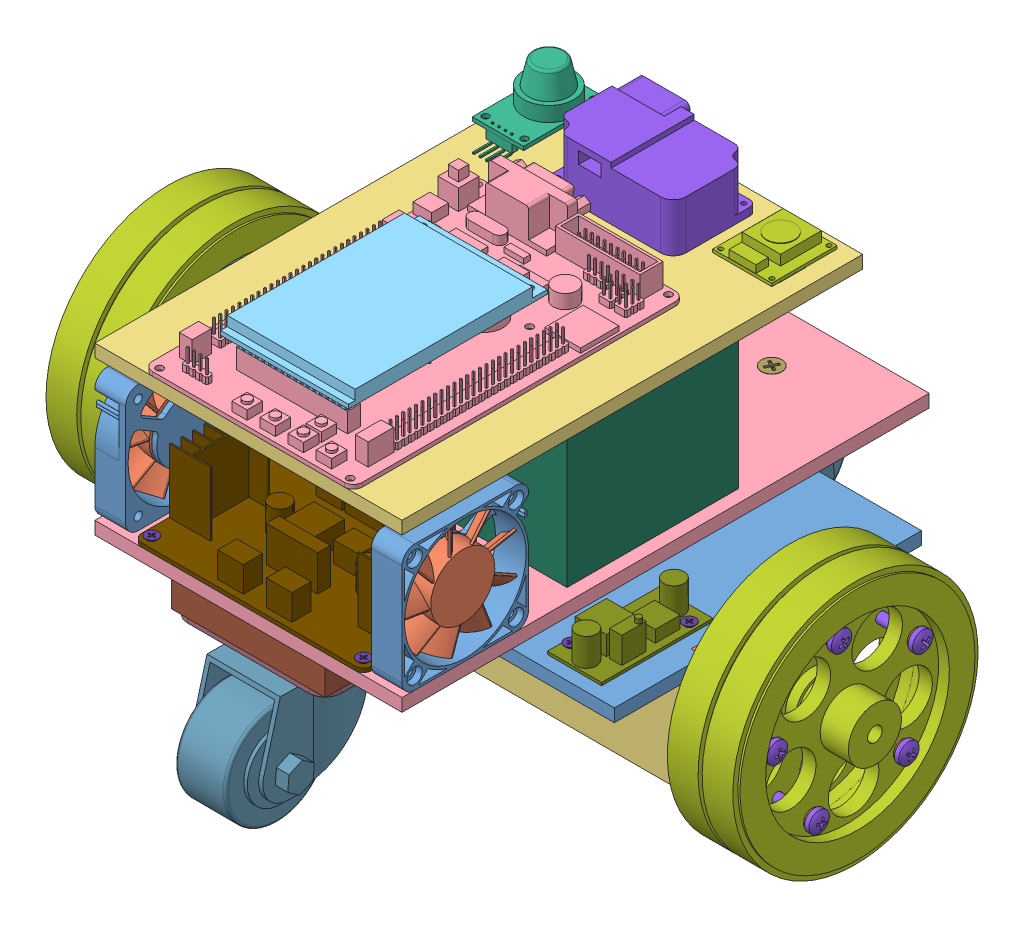
SolidWorks assembly MACM000000_MACMAssy, configuration 默认. Lengths in mm.
Overall size (283.6 176.7 243.22).
103 component instances, 26 part files, 3 mates.
Components (placement in the parent):
- MACM010000_BaseAssy-1: MACM010000_BaseAssy [默认] at (-30.595 3.8524 77.6) size (283.6 149.04 243.22)
  - MACM010100_Base-1: MACM010100_Base [默认] at (-8.5802 22.7565 6) size (200 55 206)
    - MACM010103_BasePlateC-1: MACM010103_BasePlateC [默认] at (5.4574 14.5542 200) size (200 5 120)
    - MACM010101_BasePlateA-1: MACM010101_BasePlateA [默认] at (-89.5426 -5.4458 200) x (0 0 1) z (0 -1 0) size (50 5 50)
    - MACM010101_BasePlateA-3: MACM010101_BasePlateA [默认] at (105.4574 -5.4458 200) x (0 0 1) z (0 -1 0) size (50 5 50)
    - MACM010102_BasePlateB-1: MACM010102_BasePlateB [默认] at (5.4574 -7.9458 225) x (-1 0 0) z (0 -1 0) size (200 5 45)
    - MACM010102_BasePlateB-3: MACM010102_BasePlateB [默认] at (5.4574 -7.9458 180) x (-1 0 0) z (0 -1 0) size (200 5 45)
    - MACM010104_BasePlateD-1: MACM010104_BasePlateD [默认] at (5.4574 19.5542 200) x (0 0 1) z (-1 0 0) size (206 5 120)
  - MACM010001_Motor_75w-1: MACM010001_Motor_75w [默认] at (-98.1229 17.3107 206) size (106.7 37 37)
  - MACM010001_Motor_75w-3: MACM010001_Motor_75w [默认] at (91.8771 17.3107 206) x (-1 0 0) z (0 0 -1) size (106.7 37 37)
  - GB_CROSS_SCREWS_TYPE1 M3X12-12  H type-N-1: GB_CROSS_SCREWS_TYPE1 M3X12-12  H type-N [GB_CROSS_SCREWS_TYPE1 M3X12-12  H type-N] at (-105.5229 30.7341 198.25) size (14.39 5.6 5.6)
  - GB_CROSS_SCREWS_TYPE1 M3X12-12  H type-N-2: GB_CROSS_SCREWS_TYPE1 M3X12-12  H type-N [GB_CROSS_SCREWS_TYPE1 M3X12-12  H type-N] at (-105.5229 17.3107 190.5) x (1 0 0) z (0 0.866025 0.5) size (14.39 5.6 5.6)
  - GB_CROSS_SCREWS_TYPE1 M3X12-12  H type-N-3: GB_CROSS_SCREWS_TYPE1 M3X12-12  H type-N [GB_CROSS_SCREWS_TYPE1 M3X12-12  H type-N] at (-105.5229 3.8873 198.25) x (1 0 0) z (0 0.866025 -0.5) size (14.39 5.6 5.6)
  - GB_CROSS_SCREWS_TYPE1 M3X12-12  H type-N-4: GB_CROSS_SCREWS_TYPE1 M3X12-12  H type-N [GB_CROSS_SCREWS_TYPE1 M3X12-12  H type-N] at (-105.5229 3.8873 213.75) x (1 0 0) z (0 0 -1) size (14.39 5.6 5.6)
  - GB_CROSS_SCREWS_TYPE1 M3X12-12  H type-N-5: GB_CROSS_SCREWS_TYPE1 M3X12-12  H type-N [GB_CROSS_SCREWS_TYPE1 M3X12-12  H type-N] at (-105.5229 17.3107 221.5) x (1 0 0) z (0 -0.866025 -0.5) size (14.39 5.6 5.6)
  - GB_CROSS_SCREWS_TYPE1 M3X12-12  H type-N-6: GB_CROSS_SCREWS_TYPE1 M3X12-12  H type-N [GB_CROSS_SCREWS_TYPE1 M3X12-12  H type-N] at (-105.5229 30.7341 213.75) x (1 0 0) z (0 -0.866025 0.5) size (14.39 5.6 5.6)
  - GB_CROSS_SCREWS_TYPE1 M3X12-12  H type-N-8: GB_CROSS_SCREWS_TYPE1 M3X12-12  H type-N [GB_CROSS_SCREWS_TYPE1 M3X12-12  H type-N] at (99.2771 3.8873 213.75) x (-1 0 0) z (0 -0.924225 -0.381849) size (14.39 5.6 5.6)
  - GB_CROSS_SCREWS_TYPE1 M3X12-12  H type-N-9: GB_CROSS_SCREWS_TYPE1 M3X12-12  H type-N [GB_CROSS_SCREWS_TYPE1 M3X12-12  H type-N] at (99.2771 3.8873 198.25) x (-1 0 0) z (0 -0.131421 -0.991327) size (14.39 5.6 5.6)
  - GB_CROSS_SCREWS_TYPE1 M3X12-12  H type-N-10: GB_CROSS_SCREWS_TYPE1 M3X12-12  H type-N [GB_CROSS_SCREWS_TYPE1 M3X12-12  H type-N] at (99.2771 17.3107 190.5) x (-1 0 0) z (0 0.792804 -0.609477) size (14.39 5.6 5.6)
  - GB_CROSS_SCREWS_TYPE1 M3X12-12  H type-N-11: GB_CROSS_SCREWS_TYPE1 M3X12-12  H type-N [GB_CROSS_SCREWS_TYPE1 M3X12-12  H type-N] at (99.2771 30.7341 198.25) x (-1 0 0) z (0 0.924225 0.381849) size (14.39 5.6 5.6)
  - GB_CROSS_SCREWS_TYPE1 M3X12-12  H type-N-12: GB_CROSS_SCREWS_TYPE1 M3X12-12  H type-N [GB_CROSS_SCREWS_TYPE1 M3X12-12  H type-N] at (99.2771 30.7341 213.75) x (-1 0 0) z (0 0.131421 0.991327) size (14.39 5.6 5.6)
  - GB_CROSS_SCREWS_TYPE1 M3X12-12  H type-N-13: GB_CROSS_SCREWS_TYPE1 M3X12-12  H type-N [GB_CROSS_SCREWS_TYPE1 M3X12-12  H type-N] at (99.2771 17.3107 221.5) x (-1 0 0) z (0 -0.792804 0.609477) size (14.39 5.6 5.6)
  - MACM010300_DrivingWheel-1: MACM010300_DrivingWheel [默认] at (94.5266 112.8584 231.864) x (-1 0 0) z (0 -0.924225 -0.381849) size (40.8 108.78 108.78)
    - MACM010301_DrivingWheel-1: MACM010301_DrivingWheel [默认] at (-30.5506 -9.9077 91.7141) size (20.4 95.8 95.8)
    - MACM010301_DrivingWheel-2: MACM010301_DrivingWheel [默认] at (-16.9506 -9.9077 91.7141) x (-1 0 0) z (0 -0.989252 -0.146219) size (20.4 95.8 95.8)
    - GB_CROSS_SCREWS_TYPE1 M4X25-25  H type-N-1: GB_CROSS_SCREWS_TYPE1 M4X25-25  H type-N [GB_CROSS_SCREWS_TYPE1 M4X25-25  H type-N] at (-37.3506 -2.9981 62.2638) size (28.07 8 8)
    - GB_FASTENER_WASHER_SW 4-1: GB_FASTENER_WASHER_SW 4 [GB_FASTENER_WASHER_SW 4] at (-33.1506 -2.9981 62.2638) x (0 0 -1) z (1 0 0) size (6.6 6.6 1.1)
    - GB_FASTENER_NUT_SNAB1 M4-N-1: GB_FASTENER_NUT_SNAB1 M4-N [GB_FASTENER_NUT_SNAB1 M4-N] at (-14.3506 -2.9981 62.2638) x (0 0 1) z (-1 0 0) size (8.08 7 3.2)
    - GB_FASTENER_NUT_SNAB1 M4-N-2: GB_FASTENER_NUT_SNAB1 M4-N [GB_FASTENER_NUT_SNAB1 M4-N] at (-14.3506 -35.7814 76.042) x (0 0.951057 0.309017) z (-1 0 0) size (8.08 7 3.2)
    - GB_FASTENER_NUT_SNAB1 M4-N-3: GB_FASTENER_NUT_SNAB1 M4-N [GB_FASTENER_NUT_SNAB1 M4-N] at (-14.3506 -32.8082 111.4785) x (0 0.587785 -0.809017) z (-1 0 0) size (8.08 7 3.2)
    - GB_FASTENER_NUT_SNAB1 M4-N-4: GB_FASTENER_NUT_SNAB1 M4-N [GB_FASTENER_NUT_SNAB1 M4-N] at (-14.3506 1.8127 119.6012) x (0 -0.587785 -0.809017) z (-1 0 0) size (8.08 7 3.2)
    - GB_FASTENER_NUT_SNAB1 M4-N-5: GB_FASTENER_NUT_SNAB1 M4-N [GB_FASTENER_NUT_SNAB1 M4-N] at (-14.3506 20.2364 89.1849) x (0 -0.951057 0.309017) z (-1 0 0) size (8.08 7 3.2)
    - GB_FASTENER_WASHER_SW 4-2: GB_FASTENER_WASHER_SW 4 [GB_FASTENER_WASHER_SW 4] at (-33.1506 -35.7814 76.042) x (0 -0.951057 -0.309017) z (1 0 0) size (6.6 6.6 1.1)
    - GB_FASTENER_WASHER_SW 4-3: GB_FASTENER_WASHER_SW 4 [GB_FASTENER_WASHER_SW 4] at (-33.1506 -32.8082 111.4785) x (0 -0.587785 0.809017) z (1 0 0) size (6.6 6.6 1.1)
    - GB_FASTENER_WASHER_SW 4-4: GB_FASTENER_WASHER_SW 4 [GB_FASTENER_WASHER_SW 4] at (-33.1506 1.8127 119.6012) x (0 0.587785 0.809017) z (1 0 0) size (6.6 6.6 1.1)
    - GB_FASTENER_WASHER_SW 4-5: GB_FASTENER_WASHER_SW 4 [GB_FASTENER_WASHER_SW 4] at (-33.1506 20.2364 89.1849) x (0 0.951057 -0.309017) z (1 0 0) size (6.6 6.6 1.1)
    - GB_CROSS_SCREWS_TYPE1 M4X25-25  H type-N-2: GB_CROSS_SCREWS_TYPE1 M4X25-25  H type-N [GB_CROSS_SCREWS_TYPE1 M4X25-25  H type-N] at (-37.3506 -35.7814 76.042) x (1 0 0) z (0 0.951057 0.309017) size (28.07 8 8)
    - GB_CROSS_SCREWS_TYPE1 M4X25-25  H type-N-3: GB_CROSS_SCREWS_TYPE1 M4X25-25  H type-N [GB_CROSS_SCREWS_TYPE1 M4X25-25  H type-N] at (-37.3506 -32.8082 111.4785) x (1 0 0) z (0 0.587785 -0.809017) size (28.07 8 8)
    - GB_CROSS_SCREWS_TYPE1 M4X25-25  H type-N-4: GB_CROSS_SCREWS_TYPE1 M4X25-25  H type-N [GB_CROSS_SCREWS_TYPE1 M4X25-25  H type-N] at (-37.3506 1.8127 119.6012) x (1 0 0) z (0 -0.587785 -0.809017) size (28.07 8 8)
    - GB_CROSS_SCREWS_TYPE1 M4X25-25  H type-N-5: GB_CROSS_SCREWS_TYPE1 M4X25-25  H type-N [GB_CROSS_SCREWS_TYPE1 M4X25-25  H type-N] at (-37.3506 20.2364 89.1849) x (1 0 0) z (0 -0.951057 0.309017) size (28.07 8 8)
  - MACM010300_DrivingWheel-3: MACM010300_DrivingWheel [默认] at (-100.7723 34.2184 114.2859) size (40.8 108.78 108.78)
    - MACM010301_DrivingWheel-1: MACM010301_DrivingWheel [默认] at (-30.5506 -9.9077 91.7141) size (20.4 95.8 95.8)
    - MACM010301_DrivingWheel-2: MACM010301_DrivingWheel [默认] at (-16.9506 -9.9077 91.7141) x (-1 0 0) z (0 -0.989252 -0.146219) size (20.4 95.8 95.8)
    - GB_CROSS_SCREWS_TYPE1 M4X25-25  H type-N-1: GB_CROSS_SCREWS_TYPE1 M4X25-25  H type-N [GB_CROSS_SCREWS_TYPE1 M4X25-25  H type-N] at (-37.3506 -2.9981 62.2638) size (28.07 8 8)
    - GB_FASTENER_WASHER_SW 4-1: GB_FASTENER_WASHER_SW 4 [GB_FASTENER_WASHER_SW 4] at (-33.1506 -2.9981 62.2638) x (0 0 -1) z (1 0 0) size (6.6 6.6 1.1)
    - GB_FASTENER_NUT_SNAB1 M4-N-1: GB_FASTENER_NUT_SNAB1 M4-N [GB_FASTENER_NUT_SNAB1 M4-N] at (-14.3506 -2.9981 62.2638) x (0 0 1) z (-1 0 0) size (8.08 7 3.2)
    - GB_FASTENER_NUT_SNAB1 M4-N-2: GB_FASTENER_NUT_SNAB1 M4-N [GB_FASTENER_NUT_SNAB1 M4-N] at (-14.3506 -35.7814 76.042) x (0 0.951057 0.309017) z (-1 0 0) size (8.08 7 3.2)
    - GB_FASTENER_NUT_SNAB1 M4-N-3: GB_FASTENER_NUT_SNAB1 M4-N [GB_FASTENER_NUT_SNAB1 M4-N] at (-14.3506 -32.8082 111.4785) x (0 0.587785 -0.809017) z (-1 0 0) size (8.08 7 3.2)
    - GB_FASTENER_NUT_SNAB1 M4-N-4: GB_FASTENER_NUT_SNAB1 M4-N [GB_FASTENER_NUT_SNAB1 M4-N] at (-14.3506 1.8127 119.6012) x (0 -0.587785 -0.809017) z (-1 0 0) size (8.08 7 3.2)
    - GB_FASTENER_NUT_SNAB1 M4-N-5: GB_FASTENER_NUT_SNAB1 M4-N [GB_FASTENER_NUT_SNAB1 M4-N] at (-14.3506 20.2364 89.1849) x (0 -0.951057 0.309017) z (-1 0 0) size (8.08 7 3.2)
    - GB_FASTENER_WASHER_SW 4-2: GB_FASTENER_WASHER_SW 4 [GB_FASTENER_WASHER_SW 4] at (-33.1506 -35.7814 76.042) x (0 -0.951057 -0.309017) z (1 0 0) size (6.6 6.6 1.1)
    - GB_FASTENER_WASHER_SW 4-3: GB_FASTENER_WASHER_SW 4 [GB_FASTENER_WASHER_SW 4] at (-33.1506 -32.8082 111.4785) x (0 -0.587785 0.809017) z (1 0 0) size (6.6 6.6 1.1)
    - GB_FASTENER_WASHER_SW 4-4: GB_FASTENER_WASHER_SW 4 [GB_FASTENER_WASHER_SW 4] at (-33.1506 1.8127 119.6012) x (0 0.587785 0.809017) z (1 0 0) size (6.6 6.6 1.1)
    - GB_FASTENER_WASHER_SW 4-5: GB_FASTENER_WASHER_SW 4 [GB_FASTENER_WASHER_SW 4] at (-33.1506 20.2364 89.1849) x (0 0.951057 -0.309017) z (1 0 0) size (6.6 6.6 1.1)
    - GB_CROSS_SCREWS_TYPE1 M4X25-25  H type-N-2: GB_CROSS_SCREWS_TYPE1 M4X25-25  H type-N [GB_CROSS_SCREWS_TYPE1 M4X25-25  H type-N] at (-37.3506 -35.7814 76.042) x (1 0 0) z (0 0.951057 0.309017) size (28.07 8 8)
    - GB_CROSS_SCREWS_TYPE1 M4X25-25  H type-N-3: GB_CROSS_SCREWS_TYPE1 M4X25-25  H type-N [GB_CROSS_SCREWS_TYPE1 M4X25-25  H type-N] at (-37.3506 -32.8082 111.4785) x (1 0 0) z (0 0.587785 -0.809017) size (28.07 8 8)
    - GB_CROSS_SCREWS_TYPE1 M4X25-25  H type-N-4: GB_CROSS_SCREWS_TYPE1 M4X25-25  H type-N [GB_CROSS_SCREWS_TYPE1 M4X25-25  H type-N] at (-37.3506 1.8127 119.6012) x (1 0 0) z (0 -0.587785 -0.809017) size (28.07 8 8)
    - GB_CROSS_SCREWS_TYPE1 M4X25-25  H type-N-5: GB_CROSS_SCREWS_TYPE1 M4X25-25  H type-N [GB_CROSS_SCREWS_TYPE1 M4X25-25  H type-N] at (-37.3506 20.2364 89.1849) x (1 0 0) z (0 -0.951057 0.309017) size (28.07 8 8)
  - MACM010200_UniversalWheelAssy-1: MACM010200_UniversalWheelAssy [默认] at (-2.2458 42.1931 227.5) x (-1 0 0) z (0 0 1) size (60 63.2 61.61)
    - MACM010201_UniversalWheelBase-1: MACM010201_UniversalWheelBase [默认] at (0.8771 -0.1176 60) size (60 10 43)
    - GB_WOOD_SCREWS_TYPE135 4X12-N-1: GB_WOOD_SCREWS_TYPE135 4X12-N [GB_WOOD_SCREWS_TYPE135 4X12-N] at (-21.6229 12.5624 45) x (0 -1 0) z (0.116507 0 0.99319) size (12 8 8)
    - GB_WOOD_SCREWS_TYPE135 4X12-N-5: GB_WOOD_SCREWS_TYPE135 4X12-N [GB_WOOD_SCREWS_TYPE135 4X12-N] at (23.3771 12.5624 75) x (0 -1 0) z (0.108363 0 0.994111) size (12 8 8)
    - GB_WOOD_SCREWS_TYPE135 4X12-N-7: GB_WOOD_SCREWS_TYPE135 4X12-N [GB_WOOD_SCREWS_TYPE135 4X12-N] at (23.3771 12.5624 45) x (0 -1 0) z (0.108363 0 0.994111) size (12 8 8)
    - GB_WOOD_SCREWS_TYPE135 4X12-N-9: GB_WOOD_SCREWS_TYPE135 4X12-N [GB_WOOD_SCREWS_TYPE135 4X12-N] at (-21.6229 12.5624 75) x (0 -1 0) z (0.108363 0 0.994111) size (12 8 8)
    - MACM010210_UniversalWheel-1: MACM010210_UniversalWheel [默认] at (60.8771 11.5671 62.179) x (0 0 1) z (-1 0 0) size (61.61 53.2 60)
      - MACM010211_UniversalWheelA_1.5inch-1: MACM010211_UniversalWheelA_1.5inch [默认] at (-2.179 -1.6848 60) size (43 6.68 60)
      - MACM010212_UniversalWheelB_1.5inch-1: MACM010212_UniversalWheelB_1.5inch [默认] at (-2.179 -1.6848 60) x (-0.005663 0 -0.999984) z (0.999984 0 -0.005663) size (38.6 46.52 57.75)
  - GB_WOOD_SCREWS_TYPE135 4X12-N-9: GB_WOOD_SCREWS_TYPE135 4X12-N [GB_WOOD_SCREWS_TYPE135 4X12-N] at (16.8771 47.4107 287.5) x (0 -1 0) z (-0.453005 0 0.891508) size (12 8 8)
  - GB_WOOD_SCREWS_TYPE135 4X12-N-3: GB_WOOD_SCREWS_TYPE135 4X12-N [GB_WOOD_SCREWS_TYPE135 4X12-N] at (-23.1229 47.4107 287.5) x (0 -1 0) z (-0.453005 0 0.891508) size (12 8 8)
  - MACM010200_UniversalWheelAssy-3: MACM010200_UniversalWheelAssy [默认] at (-3.9999 42.1931 184.5) x (1 0 0) z (0 0 -1) size (60 63.2 61.61)
    - MACM010201_UniversalWheelBase-1: MACM010201_UniversalWheelBase [默认] at (0.8771 -0.1176 60) size (60 10 43)
    - GB_WOOD_SCREWS_TYPE135 4X12-N-1: GB_WOOD_SCREWS_TYPE135 4X12-N [GB_WOOD_SCREWS_TYPE135 4X12-N] at (-21.6229 12.5624 45) x (0 -1 0) z (0.116507 0 0.99319) size (12 8 8)
    - GB_WOOD_SCREWS_TYPE135 4X12-N-5: GB_WOOD_SCREWS_TYPE135 4X12-N [GB_WOOD_SCREWS_TYPE135 4X12-N] at (23.3771 12.5624 75) x (0 -1 0) z (0.108363 0 0.994111) size (12 8 8)
    - GB_WOOD_SCREWS_TYPE135 4X12-N-7: GB_WOOD_SCREWS_TYPE135 4X12-N [GB_WOOD_SCREWS_TYPE135 4X12-N] at (23.3771 12.5624 45) x (0 -1 0) z (0.108363 0 0.994111) size (12 8 8)
    - GB_WOOD_SCREWS_TYPE135 4X12-N-9: GB_WOOD_SCREWS_TYPE135 4X12-N [GB_WOOD_SCREWS_TYPE135 4X12-N] at (-21.6229 12.5624 75) x (0 -1 0) z (0.108363 0 0.994111) size (12 8 8)
    - MACM010210_UniversalWheel-1: MACM010210_UniversalWheel [默认] at (60.8771 11.5671 62.179) x (0 0 1) z (-1 0 0) size (61.61 53.2 60)
      - MACM010211_UniversalWheelA_1.5inch-1: MACM010211_UniversalWheelA_1.5inch [默认] at (-2.179 -1.6848 60) size (43 6.68 60)
      - MACM010212_UniversalWheelB_1.5inch-1: MACM010212_UniversalWheelB_1.5inch [默认] at (-2.179 -1.6848 60) x (-0.005663 0 -0.999984) z (0.999984 0 -0.005663) size (38.6 46.52 57.75)
  - GB_WOOD_SCREWS_TYPE135 4X12-N-11: GB_WOOD_SCREWS_TYPE135 4X12-N [GB_WOOD_SCREWS_TYPE135 4X12-N] at (16.8771 47.4107 124.5) x (0 -1 0) z (-0.453005 0 0.891508) size (12 8 8)
  - GB_WOOD_SCREWS_TYPE135 4X12-N-13: GB_WOOD_SCREWS_TYPE135 4X12-N [GB_WOOD_SCREWS_TYPE135 4X12-N] at (-23.1229 47.4107 124.5) x (0 -1 0) z (-0.453005 0 0.891508) size (12 8 8)
  - MACM010003_Battery-1: MACM010003_Battery [默认] at (-3.1229 74.8107 206) x (0 -1 0) z (1 0 0) size (55 67 110)
  - MACM010004_Transformer_12v5v-1: MACM010004_Transformer_12v5v [默认] at (76.2771 42.3107 239.25) size (21.2 13 43.5)
  - GB_WOOD_SCREWS_TYPE135 2.5X8-N-1: GB_WOOD_SCREWS_TYPE135 2.5X8-N [GB_WOOD_SCREWS_TYPE135 2.5X8-N] at (68.2771 44.4107 254.4) x (0 -1 0) z (0 0 1) size (8 5 5)
  - GB_WOOD_SCREWS_TYPE135 2.5X8-N-3: GB_WOOD_SCREWS_TYPE135 2.5X8-N [GB_WOOD_SCREWS_TYPE135 2.5X8-N] at (84.2771 44.4107 224.1) x (0 -1 0) z (0 0 1) size (8 5 5)
  - MACM010002_MotorDriver-1: MACM010002_MotorDriver [默认] at (-3.1229 47.3107 279) x (-1 0 0) z (0 0 -1) size (90 26.5 60)
  - GB_WOOD_SCREWS_TYPE135 2.5X8-N-5: GB_WOOD_SCREWS_TYPE135 2.5X8-N [GB_WOOD_SCREWS_TYPE135 2.5X8-N] at (-44.4729 49.8107 305.4) x (0 -1 0) z (0 0 1) size (8 5 5)
  - GB_WOOD_SCREWS_TYPE135 2.5X8-N-7: GB_WOOD_SCREWS_TYPE135 2.5X8-N [GB_WOOD_SCREWS_TYPE135 2.5X8-N] at (38.2271 49.8107 305.4) x (0 -1 0) z (0 0 1) size (8 5 5)
  - GB_WOOD_SCREWS_TYPE135 2.5X8-N-9: GB_WOOD_SCREWS_TYPE135 2.5X8-N [GB_WOOD_SCREWS_TYPE135 2.5X8-N] at (-44.4729 49.8107 252.6) x (0 -1 0) z (0 0 1) size (8 5 5)
  - GB_WOOD_SCREWS_TYPE135 2.5X8-N-11: GB_WOOD_SCREWS_TYPE135 2.5X8-N [GB_WOOD_SCREWS_TYPE135 2.5X8-N] at (38.2271 49.8107 252.6) x (0 -1 0) z (0 0 1) size (8 5 5)
  - MACM010500_Fan_50X50X12-1: MACM010500_Fan_50X50X12 [默认] at (50.4938 71.5842 234.75) x (0 -1 0) z (0 0 1) size (52.76 12.48 52.76)
    - MACM010501_FanShell_50X50X12-1: MACM010501_FanShell_50X50X12 [默认] at (-0.4765 -5.5967 49.5) size (49.5 12.48 49.5)
    - MACM010502_Fanblade_50X50X12-1: MACM010502_Fanblade_50X50X12 [默认] at (-0.4765 1.4033 49.5) x (-0.987133 0 -0.1599) z (-0.1599 0 0.987133) size (46 8.03 46)
  - MACM010500_Fan_50X50X12-3: MACM010500_Fan_50X50X12 [默认] at (-56.7396 71.5842 333.75) x (0 -1 0) z (0 0 -1) size (52.76 12.48 52.76)
    - MACM010501_FanShell_50X50X12-1: MACM010501_FanShell_50X50X12 [默认] at (-0.4765 -5.5967 49.5) size (49.5 12.48 49.5)
    - MACM010502_Fanblade_50X50X12-1: MACM010502_Fanblade_50X50X12 [默认] at (-0.4765 1.4033 49.5) x (-0.987133 0 -0.1599) z (-0.1599 0 0.987133) size (46 8.03 46)
- MACM020000_CenterAssy-1: MACM020000_CenterAssy [默认] at (146.2821 113.6624 271.6911) x (0 0 1) z (-1 0 0) size (180 27.66 120)
  - MACM020001_CenterBoard-1: MACM020001_CenterBoard [默认] at (24.9089 -7.4993 180) size (180 5 120)
  - MACM020100_STM32Assy-1: MACM020100_STM32Assy [默认] at (-88.6911 4.1308 179.3607) x (0 0 -1) z (1 0 0) size (82 19.9 134)
    - MACM020101_STM32-1: MACM020101_STM32 [默认] at (-0.6393 -6.6301 138.9) size (82 16.3 134)
    - MACM020102_LCD-1: MACM020102_LCD [默认] at (-0.6393 6.4699 150.65) size (50 15.8 77.7)
  - MACM020211_COSensor-1: MACM020211_COSensor [默认] at (-43.8411 3.8007 225) x (0 0 -1) z (1 0 0) size (20 21.46 38.35)
  - MACM020221_CH2OSensor-1: MACM020221_CH2OSensor [默认] at (-47.3411 -0.6993 136.55) x (0 0 -1) z (1 0 0) size (23.1 6.2 25.5)
  - MACM020231_PMSensor-1: MACM020231_PMSensor [默认] at (-42.3411 0.5007 180) x (0 0 1) z (1 0 0) size (50 21 36)
Mates (geometry in assembly coordinates):
- 重合1: coincident anti-aligned: plane of MACM010000_BaseAssy-1/MACM010003_Battery-1 through (21.2821 106.1631 250.1) normal (0 1 0); plane of MACM020000_CenterAssy-1/MACM020001_CenterBoard-1 through (-33.7179 106.1631 296.6) normal (0 -1 0)
- 重合2: coincident aligned: plane of MACM010000_BaseAssy-1/MACM010100_Base-1/MACM010104_BasePlateD-1 through (-93.7179 51.1631 386.6) normal (0 0 1); plane of MACM020000_CenterAssy-1/MACM020001_CenterBoard-1 through (-93.7179 111.1631 386.6) normal (0 0 1)
- 重合3: coincident aligned: plane of MACM010000_BaseAssy-1/MACM010100_Base-1/MACM010104_BasePlateD-1 through (-93.7179 51.1631 180.6) normal (-1 0 0); plane of MACM020000_CenterAssy-1/MACM020001_CenterBoard-1 through (-93.7179 111.1631 206.6) normal (-1 0 0)
